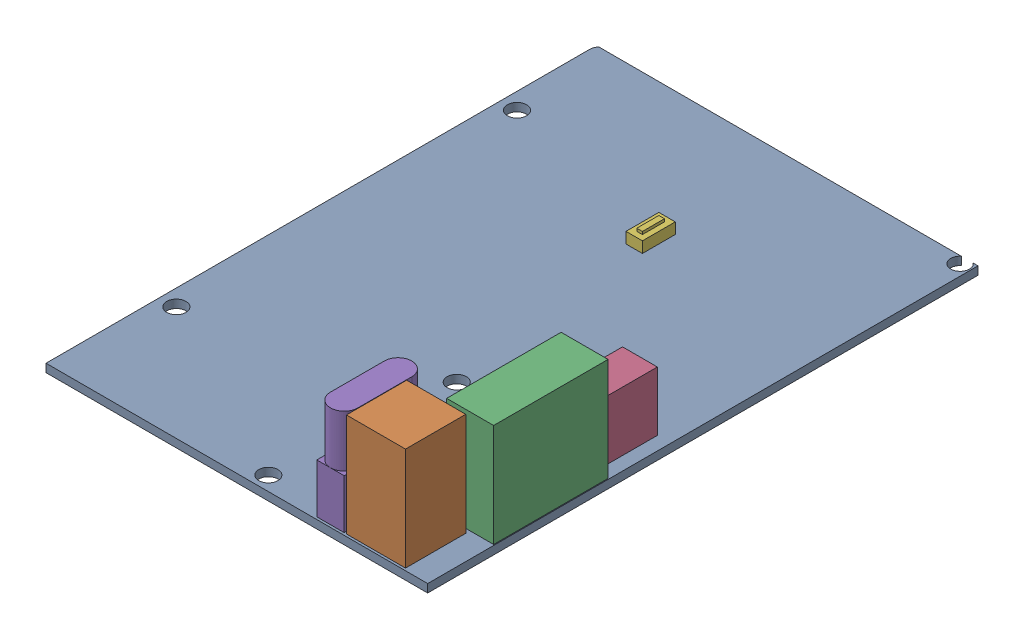
SolidWorks assembly SKR Mini E3 1.2, configuration SKR Mini E3 1.2. Lengths in mm.
Overall size (69.7 20.32 100.5).
6 component instances, 6 part files, 0 mates.
Components (placement in the parent):
- PCB-1: PCB [PCB] at origin size (69.7 1.5 100.5)
- Power IN-1: Power IN [Power IN] at (-14.6583 0 -3.0665) size (10.79 18.82 11)
- Power & Bed -1: Power & Bed  [Power & Bed ] at (-15.6583 0 -3.0665) size (8.58 18.82 20.9)
- E0-1: E0 [E0] at (-15.6583 0 -3.0665) size (6.36 10.82 10)
- Fuse-1: Fuse [Fuse] at (-14.6583 0 -3.0665) size (5 18.48 14.84)
- Reset-1: Reset [Reset] at (-4.0633 0 9.9288) size (3 2.5 6)
